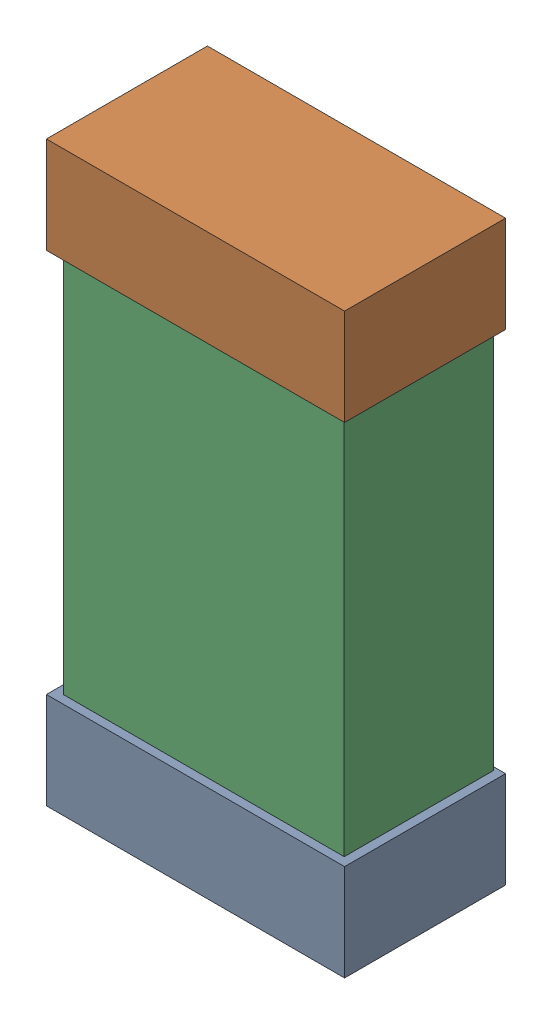
SolidWorks assembly R38, configuration Default. Lengths in mm.
Overall size (0.85 1.65 0.46).
6 component instances, 2 part files, 0 mates.
Components (placement in the parent):
- 432138512_28-1: 432138512_28 [Default] at (9.0999 49.4142 -0.8715) size (0.85 0.28 0.46)
  - Extruded-1: Extruded [Default] at origin size (0.85 0.28 0.46)
- 432138512_29-1: 432138512_29 [Default] at (9.0999 50.7857 -0.8715) size (0.85 0.28 0.46)
  - Extruded-1: Extruded [Default] at origin size (0.85 0.28 0.46)
- 432124816_14-1: 432124816_14 [Default] at (9.0999 50.0999 -0.8615) size (0.8 1.5 0.42)
  - Extruded (1)-1: Extruded (1) [Default] at origin size (0.8 1.5 0.42)
